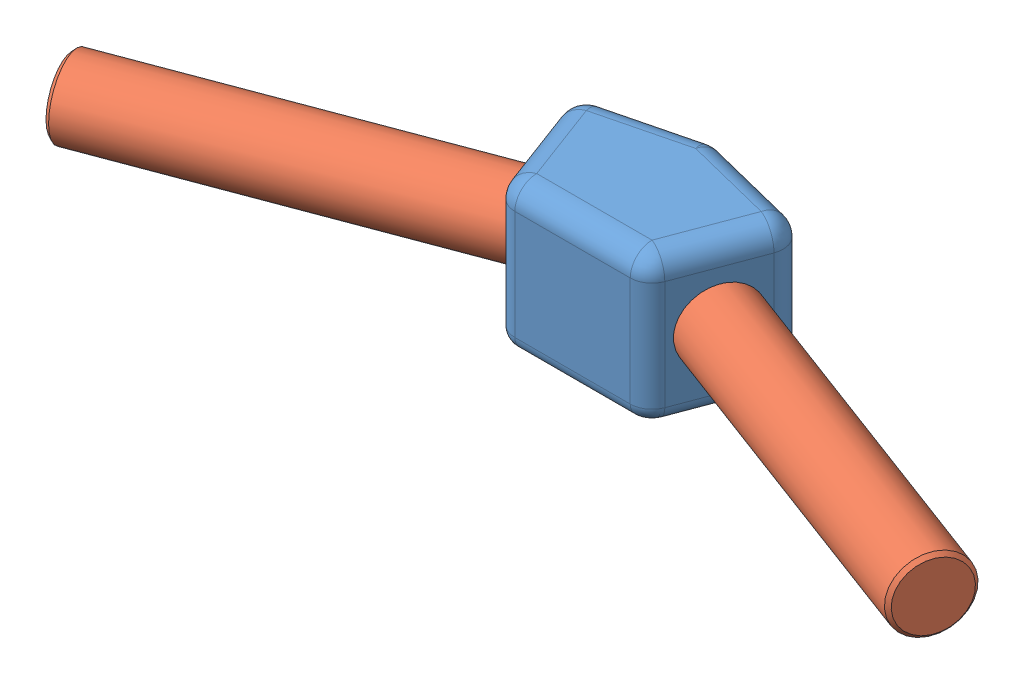
SolidWorks assembly Idler_Bent_Asm, configuration Default. Lengths in mm.
Overall size (61.61 10 17.71).
5 component instances, 2 part files, 5 mates.
Components (placement in the parent):
- IdlerBentConnector-1: IdlerBentConnector [Default] at origin size (15.01 10 9.95)
- Idler_Shaft_Bent_Half-1: Idler_Shaft_Bent_Half [Default] at (1.7228 5 -5.5009) x (0.062273 -0.984147 -0.16606) z (0.936329 0 0.351123) size (5 5 30)
- Idler_Shaft_Bent_Half-2: Idler_Shaft_Bent_Half [Default] at (-1.7228 5 -5.5009) x (-0.038499 0.993971 -0.102664) z (-0.936329 0 0.351123) size (5 5 30)
- 1037396-1: 1037396 [Default] at (-13.855 5 -0.9514) x (-0.055502 0.987428 -0.148007) z (0.346709 0.158071 0.924557) (suppressed, hidden)
- 1037396-2: 1037396 [Default] at (13.855 5 -0.9514) x (0.055502 0.987428 -0.148007) z (0.346709 -0.158071 -0.924557) (suppressed, hidden)
Mates (geometry in assembly coordinates):
- Concentric1: concentric anti-aligned: cylinder of IdlerBentConnector-1 through (1.7228 5 -5.5009) axis (0.936329 0 0.351123) radius 2.5; cylinder of Idler_Shaft_Bent_Half-1 through (29.8127 5 5.0328) axis (-0.936329 0 -0.351123) radius 2.5
- Coincident1: coincident anti-aligned: plane of IdlerBentConnector-1 through (1.7228 5 -5.5009) normal (0.936329 0 0.351123); plane of Idler_Shaft_Bent_Half-1 through (1.7228 5 -5.5009) normal (-0.936329 0 -0.351123)
- Concentric2: concentric anti-aligned: cylinder of IdlerBentConnector-1 through (-1.7228 5 -5.5009) axis (-0.936329 0 0.351123) radius 2.5; cylinder of Idler_Shaft_Bent_Half-2 through (-29.8127 5 5.0328) axis (0.936329 0 -0.351123) radius 2.5
- Coincident2: coincident anti-aligned: plane of IdlerBentConnector-1 through (-1.7228 5 -5.5009) normal (-0.936329 0 0.351123); plane of Idler_Shaft_Bent_Half-2 through (-1.7228 5 -5.5009) normal (0.936329 0 -0.351123)
- Concentric3: concentric anti-aligned: cylinder of Idler_Shaft_Bent_Half-2 through (-29.8127 5 5.0328) axis (0.936329 0 -0.351123) radius 2.5; cylinder of 1037396-1/1037396-95-2Z BEARING, 9 mm OD, 5 mm ID, 3 mm WIDTH-1 through (-20.4093 5 1.5065) axis (-0.936329 0 0.351123) radius 2.5
